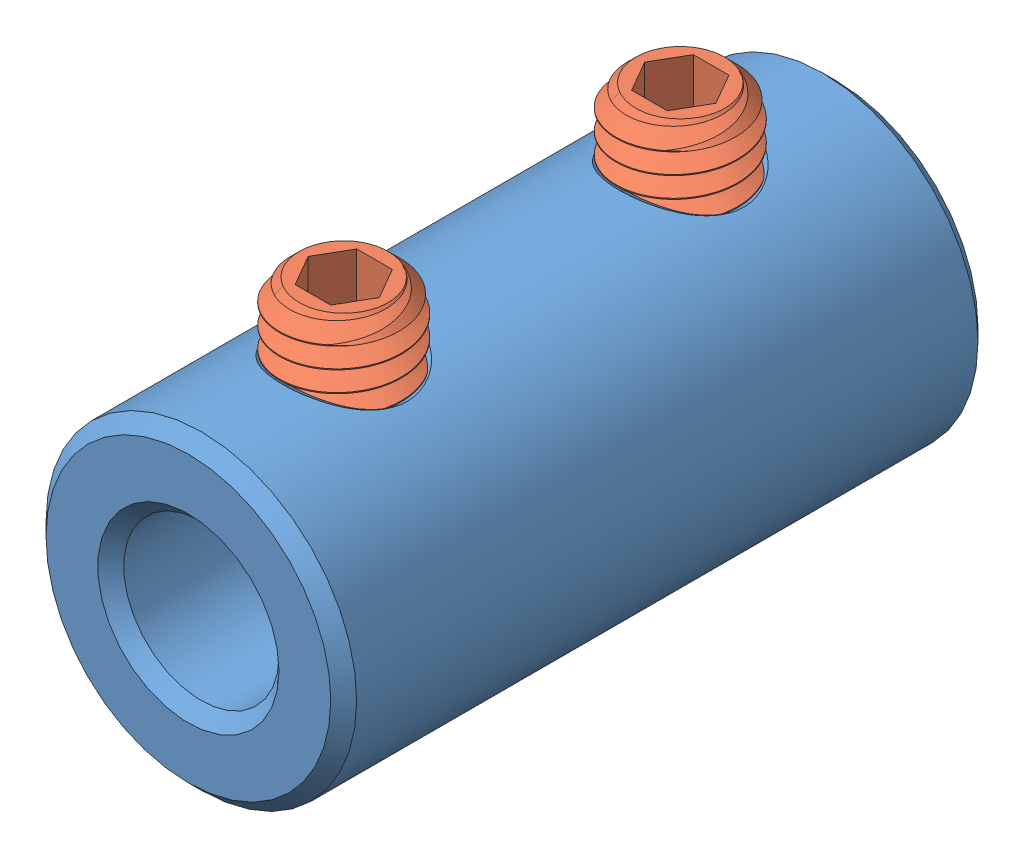
SolidWorks assembly Tetrix Coupler (Axle to Motor), configuration Default. Lengths in mm.
Overall size (12 14.54 25).
3 component instances, 2 part files, 0 mates.
Components (placement in the parent):
- Tetrix Coupler (Axle to Motor) Body-1: Tetrix Coupler (Axle to Motor) Body [Default] at origin size (12 12 25)
- Tetrix Coupler (Axle to Motor) Set Screw-1: Tetrix Coupler (Axle to Motor) Set Screw [Default] at (0 3 6.5) x (0.866025 0 0.5) z (-0.5 0 0.866025) size (4.78 5.54 4.7)
- Tetrix Coupler (Axle to Motor) Set Screw-2: Tetrix Coupler (Axle to Motor) Set Screw [Default] at (0 3 -6.5) x (0.866025 0 0.5) z (-0.5 0 0.866025) size (4.78 5.54 4.7)
